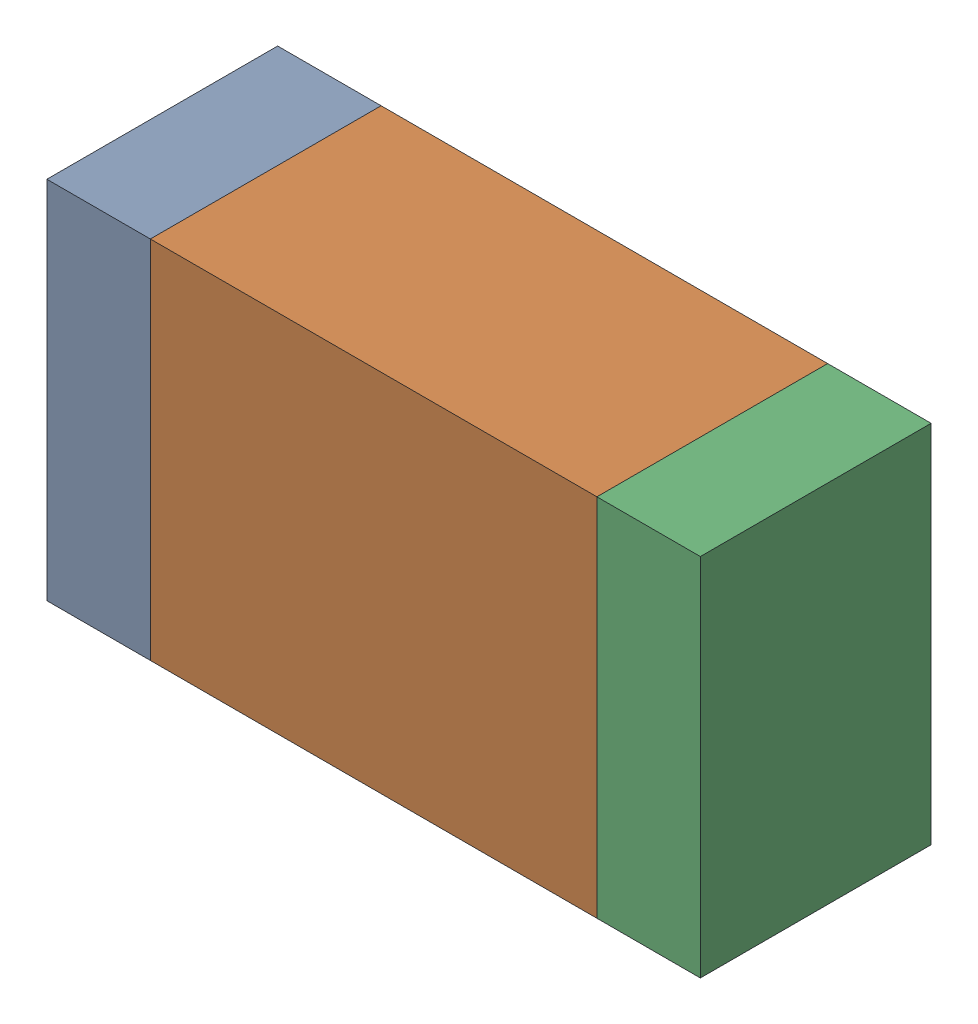
SolidWorks assembly F300_1PCB, configuration Default. Lengths in mm.
Overall size (1.7 0.95 0.6).
6 component instances, 2 part files, 0 mates.
Components (placement in the parent):
- 761615840-1: 761615840 [Default] at (159.7849 108.1001 0) size (0.27 0.95 0.6)
  - Extruded_37-1: Extruded_37 [Default] at origin size (0.27 0.95 0.6)
- 761615976-1: 761615976 [Default] at (160.4999 108.1001 0) size (1.16 0.95 0.6)
  - Extruded_38-1: Extruded_38 [Default] at origin size (1.16 0.95 0.6)
- 761615840-2: 761615840 [Default] at (161.2149 108.1001 0) size (0.27 0.95 0.6)
  - Extruded_37-1: Extruded_37 [Default] at origin size (0.27 0.95 0.6)
